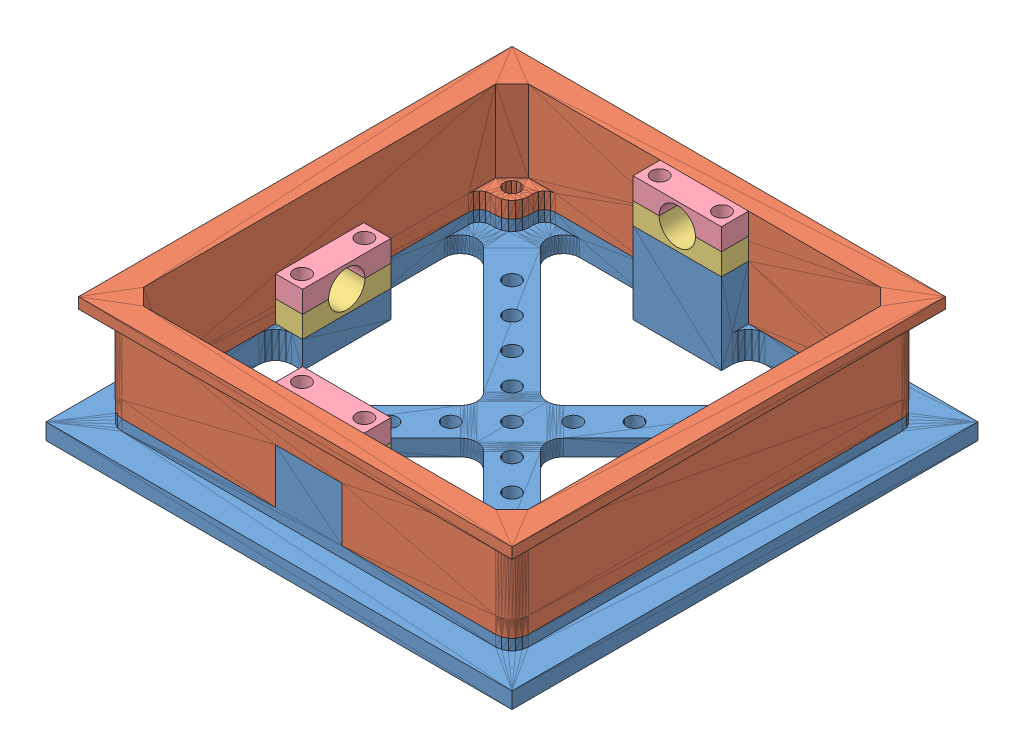
SolidWorks assembly Assem1, configuration Default. Lengths in mm.
Overall size (86 23 86).
10 component instances, 4 part files, 23 mates.
Components (placement in the parent):
- Component1_v2-1: Component1_v2 [Default] at (80.9291 -9.2822 -4.7321) x (-1 0 0) z (0 0 1) size (86 15 86)
- Component2_v2-1: Component2_v2 [Default] at (80.9291 -9.2822 -4.7321) x (-1 0 0) z (0 0 1) size (80 18 80)
- RodHatBase-1: RodHatBase [Default] at (37.9291 13.7178 2.7679) x (1 0 0) z (0 0 -1) size (16.31 4.18 5)
- RodHatTop-2: RodHatTop [Default] at (37.9291 17.7178 7.7679) size (16.31 4 5)
- RodHatBase-2: RodHatBase [Default] at (37.9291 13.7178 68.7679) x (1 0 0) z (0 0 -1) size (16.31 4.18 5)
- RodHatBase-3: RodHatBase [Default] at (7.4291 3.7178 38.2679) x (0 0 1) z (1 0 0) size (16.31 4.18 5)
- RodHatBase-4: RodHatBase [Default] at (73.4291 3.7178 38.2679) x (0 0 1) z (1 0 0) size (16.31 4.18 5)
- RodHatTop-3: RodHatTop [Default] at (37.9291 17.7178 73.7679) size (16.31 4 5)
- RodHatTop-4: RodHatTop [Default] at (7.4291 7.7178 38.2679) x (0 0 -1) z (1 0 0) size (16.31 4 5)
- RodHatTop-5: RodHatTop [Default] at (73.4291 7.7178 38.2679) x (0 0 -1) z (1 0 0) size (16.31 4 5)
Mates (geometry in assembly coordinates):
- Coincident2: coincident anti-aligned: plane of Component1_v2-1 through (80.9291 1.7178 -4.7321) normal (0 1 0); plane of Component2_v2-1 through (80.9291 1.7178 -4.7321) normal (0 -1 0)
- Coincident3: coincident anti-aligned: line of Component1_v2-1 through (44.0841 1.7178 0.7679) axis (0 1 0); line of Component2_v2-1 through (44.0841 11.7178 0.7679) axis (0 -1 0)
- Coincident5: coincident aligned: line of Component1_v2-1 through (29.7741 11.7178 7.7679) axis (1 0 0); line of RodHatBase-1 through (29.7741 11.7178 7.7679) axis (1 0 0)
- Coincident6: coincident: point of Component1_v2-1; point of RodHatBase-1
- Coincident7: coincident anti-aligned: plane of Component2_v2-1 through (80.9291 -9.2822 2.7679) normal (0 0 1); plane of RodHatBase-1 through (37.9291 13.7178 2.7679) normal (0 0 -1)
- Coincident9: coincident anti-aligned: line of RodHatBase-1 through (46.0841 15.7178 7.7679) axis (0 0 -1); line of RodHatTop-2 through (46.0841 15.7178 2.7679) axis (0 0 1)
- Coincident10: coincident: point of RodHatBase-1; point of RodHatTop-2
- Concentric1: concentric anti-aligned: circle of RodHatBase-1; circle of RodHatTop-2
- Coincident12: coincident anti-aligned: line of Component2_v2-1 through (70.4291 19.7178 2.7679) axis (-1 0 0); line of RodHatTop-2 through (29.7741 19.7178 2.7679) axis (1 0 0)
- Coincident13: coincident anti-aligned: line of Component1_v2-1 through (46.0841 11.7178 68.7679) axis (-1 0 0); line of RodHatBase-2 through (29.7741 11.7178 68.7679) axis (1 0 0)
- Coincident14: coincident: point of Component1_v2-1; point of RodHatBase-2
- Concentric2: concentric aligned: circle of RodHatBase-1; circle of RodHatBase-2
- Coincident16: coincident anti-aligned: line of Component1_v2-1 through (7.4291 1.7178 46.4229) axis (0 0 -1); line of RodHatBase-3 through (7.4291 1.7178 30.1129) axis (0 0 1)
- Coincident17: coincident: point of Component1_v2-1; point of RodHatBase-3
- Coincident20: coincident: point of Component1_v2-1; point of RodHatBase-4
- Concentric3: concentric aligned: circle of RodHatBase-3; circle of RodHatBase-4
- Coincident22: coincident aligned: line of Component1_v2-1 through (68.4291 1.7178 30.1129) axis (0 0 1); line of RodHatBase-4 through (68.4291 1.7178 30.1129) axis (0 0 1)
- Coincident25: coincident aligned: line of RodHatBase-2 through (41.2841 15.7178 68.7679) axis (1 0 0); line of RodHatTop-3 through (41.2841 15.7178 68.7679) axis (1 0 0)
- Concentric5: concentric anti-aligned: circle of RodHatBase-2; circle of RodHatTop-3
- Concentric6: concentric aligned: circle of RodHatBase-3; circle of RodHatTop-4
- Coincident28: coincident anti-aligned: line of RodHatBase-3 through (7.4291 5.7178 30.1129) axis (0 0 1); line of RodHatTop-4 through (7.4291 5.7178 34.9129) axis (0 0 -1)
- Coincident29: coincident anti-aligned: line of RodHatBase-4 through (68.4291 5.7178 41.6229) axis (0 0 1); line of RodHatTop-5 through (68.4291 5.7178 46.4229) axis (0 0 -1)
- Concentric7: concentric aligned: circle of RodHatBase-3; circle of RodHatTop-5
